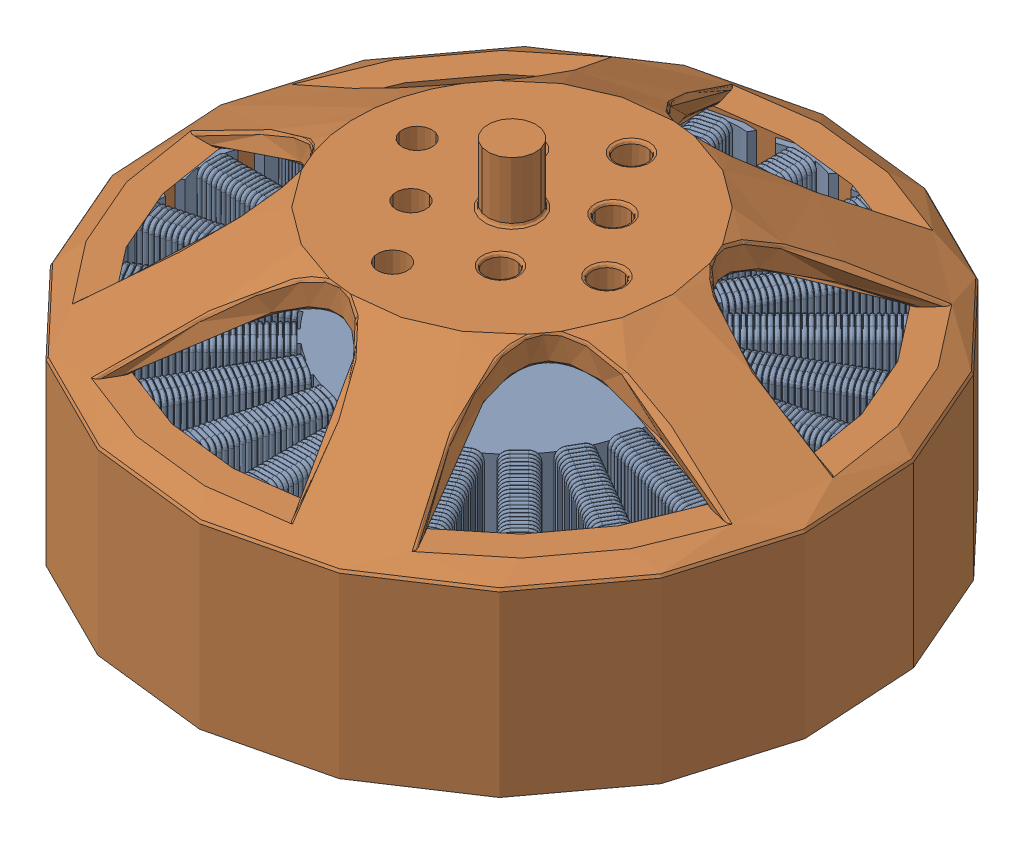
SolidWorks assembly ANTIGRAVITY MN5008 170KV, configuration Default. Lengths in mm.
Overall size (61.58 32 61.58).
2 component instances, 2 part files, 5 mates.
Components (placement in the parent):
- Stator-1: Stator [Default] at (0 4 0) size (51.31 18.52 51.31)
- Rotor-1: Rotor [Default] at (0 4 0) x (0.114014 0 -0.993479) z (0.993479 0 0.114014) size (55.6 28 55.6)
Mates (geometry in assembly coordinates):
- Coincident1: coincident aligned: plane of Stator-1 through (0 0 0) normal (0 0 1)
- Coincident2: coincident anti-aligned: plane of Stator-1 through (0 -4 0) normal (0 -1 0)
- Coincident3: coincident aligned: plane of Stator-1 through (0 0 0) normal (1 0 0)
- Coincident4: coincident anti-aligned: line of Stator-1 through (0 -0.7 0) axis (0 1 0); line of Rotor-1 through (0 33.6 0) axis (0 -1 0)
- Coincident5: coincident aligned: plane of Stator-1 through (0 0 0) normal (0 -1 0); plane of Rotor-1 through (0 0 0) normal (0 -1 0)
